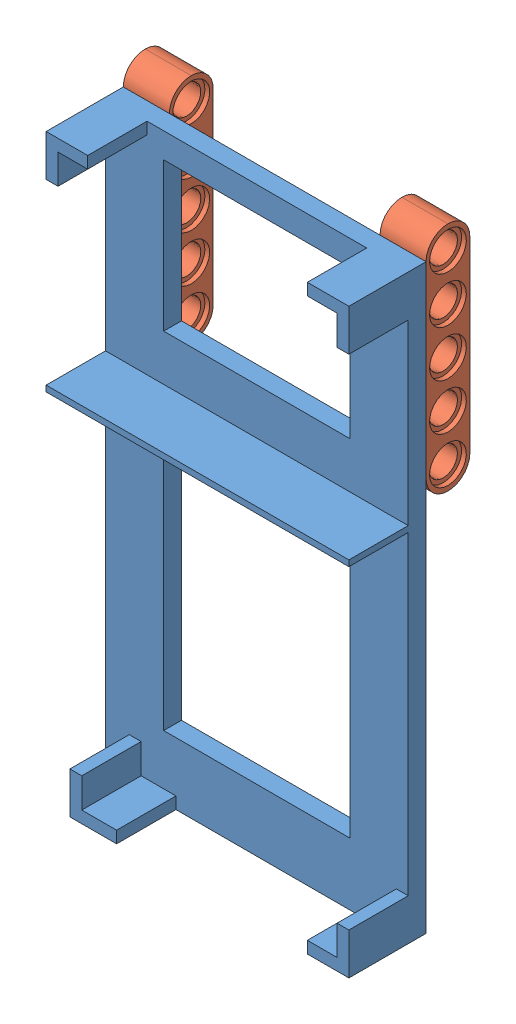
SolidWorks assembly korthållareny, configuration Default. Lengths in mm.
Overall size (51 101.69 20.38).
3 component instances, 2 part files, 7 mates.
Components (placement in the parent):
- Hållare termometer (1)-1: Hållare termometer (1) [Default] at origin size (51 98 13)
- legobeam_5-2: legobeam_5 [Default] at (43.24 62.69 -7.38) x (0 1 0) z (1 0 0) size (39 7.38 7.76)
- legobeam_5-3: legobeam_5 [Default] at (0 62.69 -7.38) x (0 1 0) z (1 0 0) size (39 7.38 7.76)
Mates (geometry in assembly coordinates):
- Coincident7: coincident: plane of Hållare termometer (1)-1 through (0 0 0) normal (0 0 -1); plane of legobeam_5-2 through (51 62.69 0) normal (0 0 1)
- Coincident8: coincident: line of legobeam_5-2 through (31.62 51 98) axis (0 0 -1); line of Hållare termometer (1)-1 through (98 51 0) axis (0 0 1)
- Parallel3: parallel: line of Hållare termometer (1)-1 through (51 0 98) axis (0 1 0); line of legobeam_5-2 through (43.24 98 -7.38) axis (1 0 0)
- Coincident13: coincident: line of Hållare termometer (1)-1 through (51 0 98) axis (0 1 0); cylinder of legobeam_5-2 through (51 98 -3.69) axis (1 0 0) radius 3.69
- Coincident14: coincident: plane of Hållare termometer (1)-1 through (0 0 0) normal (0 0 -1); plane of legobeam_5-3 through (7.76 62.69 0) normal (0 0 1)
- Coincident15: coincident: line of Hållare termometer (1)-1 through (98 0 0) axis (0 0 1); line of legobeam_5-3 through (31.62 0 98) axis (0 0 -1)
- Coincident16: coincident: line of Hållare termometer (1)-1 through (51 0 98) axis (0 1 0); cylinder of legobeam_5-3 through (7.76 98 -3.69) axis (1 0 0) radius 3.69
